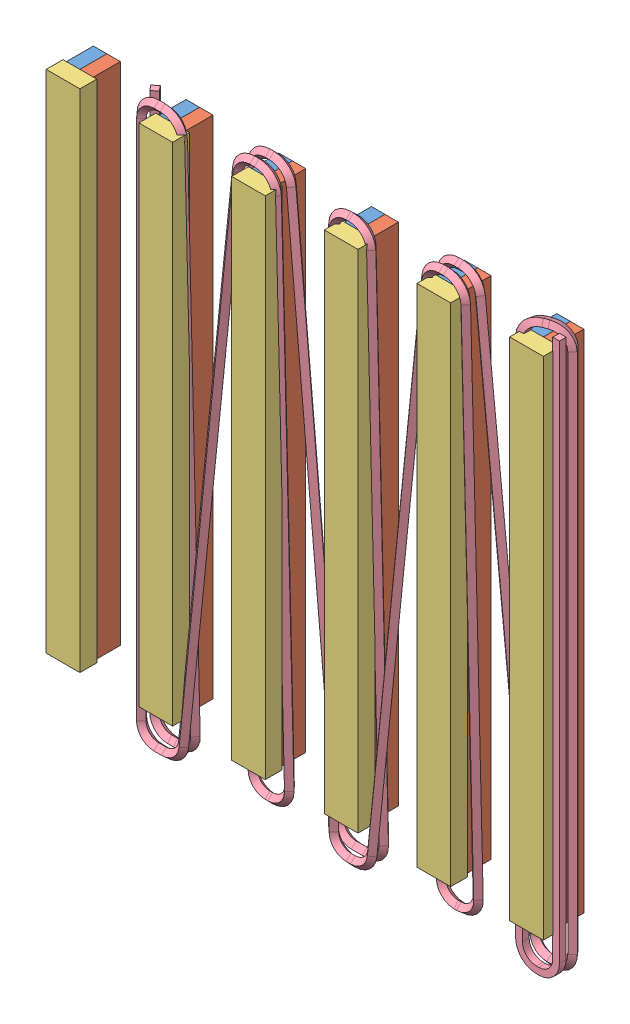
SolidWorks assembly Assem1, configuration Default. Lengths in mm.
Overall size (30.12 33.85 2.6).
26 component instances, 5 part files, 9 mates.
Components (placement in the parent):
- base_plate-1: base_plate [Default] at (-10.1205 0.0384 5.3144) size (40 40 1) (hidden)
- mag_asm-1: mag_asm [Default] at (-26.6947 1.5379 1.0766) size (1.6 30 1.6)
  - alnico_mag-1: alnico_mag [Default] at (2.3742 -16.4995 5.2378) size (0.8 30 1.6)
  - Neo_mag-1: Neo_mag [Default] at (54.7003 10.2768 5.2378) size (0.8 30 1.6)
- mag_asm-2: mag_asm [Default] at (-21.1947 1.5379 1.0766) size (1.6 30 1.6)
  - alnico_mag-1: alnico_mag [Default] at (2.3742 -16.4995 5.2378) size (0.8 30 1.6)
  - Neo_mag-1: Neo_mag [Default] at (54.7003 10.2768 5.2378) size (0.8 30 1.6)
- mag_asm-3: mag_asm [Default] at (-15.6947 1.5379 1.0766) size (1.6 30 1.6)
  - alnico_mag-1: alnico_mag [Default] at (2.3742 -16.4995 5.2378) size (0.8 30 1.6)
  - Neo_mag-1: Neo_mag [Default] at (54.7003 10.2768 5.2378) size (0.8 30 1.6)
- mag_asm-4: mag_asm [Default] at (-10.1947 1.5379 1.0766) size (1.6 30 1.6)
  - alnico_mag-1: alnico_mag [Default] at (2.3742 -16.4995 5.2378) size (0.8 30 1.6)
  - Neo_mag-1: Neo_mag [Default] at (54.7003 10.2768 5.2378) size (0.8 30 1.6)
- mag_asm-5: mag_asm [Default] at (-4.6947 1.5379 1.0766) size (1.6 30 1.6)
  - alnico_mag-1: alnico_mag [Default] at (2.3742 -16.4995 5.2378) size (0.8 30 1.6)
  - Neo_mag-1: Neo_mag [Default] at (54.7003 10.2768 5.2378) size (0.8 30 1.6)
- mag_asm-6: mag_asm [Default] at (0.8053 1.5379 1.0766) size (1.6 30 1.6)
  - alnico_mag-1: alnico_mag [Default] at (2.3742 -16.4995 5.2378) size (0.8 30 1.6)
  - Neo_mag-1: Neo_mag [Default] at (54.7003 10.2768 5.2378) size (0.8 30 1.6)
- base_header-1: base_header [Default] at (-24.3205 0.0384 8.9144) x (0 -1 0) z (0 0 -1) size (30 2 1)
- base_header-2: base_header [Default] at (-18.8205 0.0384 8.9144) x (0 -1 0) z (0 0 -1) size (30 2 1)
- base_header-3: base_header [Default] at (-13.3205 0.0384 8.9144) x (0 -1 0) z (0 0 -1) size (30 2 1)
- base_header-4: base_header [Default] at (-7.8205 0.0384 8.9144) x (0 -1 0) z (0 0 -1) size (30 2 1)
- base_header-5: base_header [Default] at (-2.3205 0.0384 8.9144) x (0 -1 0) z (0 0 -1) size (30 2 1)
- base_header-6: base_header [Default] at (3.1795 0.0384 8.9144) x (0 -1 0) z (0 0 -1) size (30 2 1)
- winding-3: winding [Default] at (4.3753 -17.2563 8.1528) x (0 -1 0) z (0 0 -1) size (33.57 25.38 1.38)
Mates (geometry in assembly coordinates):
- Coincident1: coincident anti-aligned: plane of base_plate-1 through (-10.1205 0.0384 6.3144) normal (0 0 1); plane of mag_asm-1/alnico_mag-1 through (-24.3205 -14.9616 6.3144) normal (0 0 -1)
- Distance1: distance = 5 mm aligned: plane of mag_asm-1/Neo_mag-1 through (-24.3205 15.0384 7.9144) normal (0 1 0); plane of base_plate-1 through (-30.1205 20.0384 6.3144) normal (0 1 0)
- Distance2: distance = 5 mm aligned: plane of base_plate-1 through (-30.1205 20.0384 6.3144) normal (-1 0 0); plane of mag_asm-1/alnico_mag-1 through (-25.1205 -14.9616 7.9144) normal (-1 0 0)
- Parallel3: parallel aligned: plane of base_header-1 through (-25.3205 15.0384 7.9144) normal (-1 0 0); plane of base_plate-1 through (-30.1205 20.0384 6.3144) normal (-1 0 0)
- Coincident8: coincident: line of mag_asm-1/alnico_mag-1 through (-25.1205 15.0384 7.9144) axis (0 -1 0); plane of base_header-1 through (-24.3205 0.0384 7.9144) normal (0 0 -1)
- Distance3: distance = 0.2 mm: plane of base_header-1 through (-25.3205 15.0384 7.9144) normal (-1 0 0); line of mag_asm-1/alnico_mag-1 through (-25.1205 15.0384 7.9144) axis (0 -1 0)
- Coincident10: coincident aligned: plane of mag_asm-1/alnico_mag-1 through (-24.3205 15.0384 7.9144) normal (0 1 0); plane of base_header-1 through (-25.3205 15.0384 7.9144) normal (0 1 0)
- Parallel4: parallel: line of base_plate-1 through (9.8795 20.0384 6.3144) axis (-1 0 0); line of winding-3 through (2.1753 -17.2563 7.3528) axis (-0.102488 0.994734 0)
- Parallel5: parallel: line of base_plate-1 through (-30.1205 20.0384 6.3144) axis (0 -1 0); line of winding-3 through (-3.4247 15.7437 7.3528) axis (0 -1 0)
